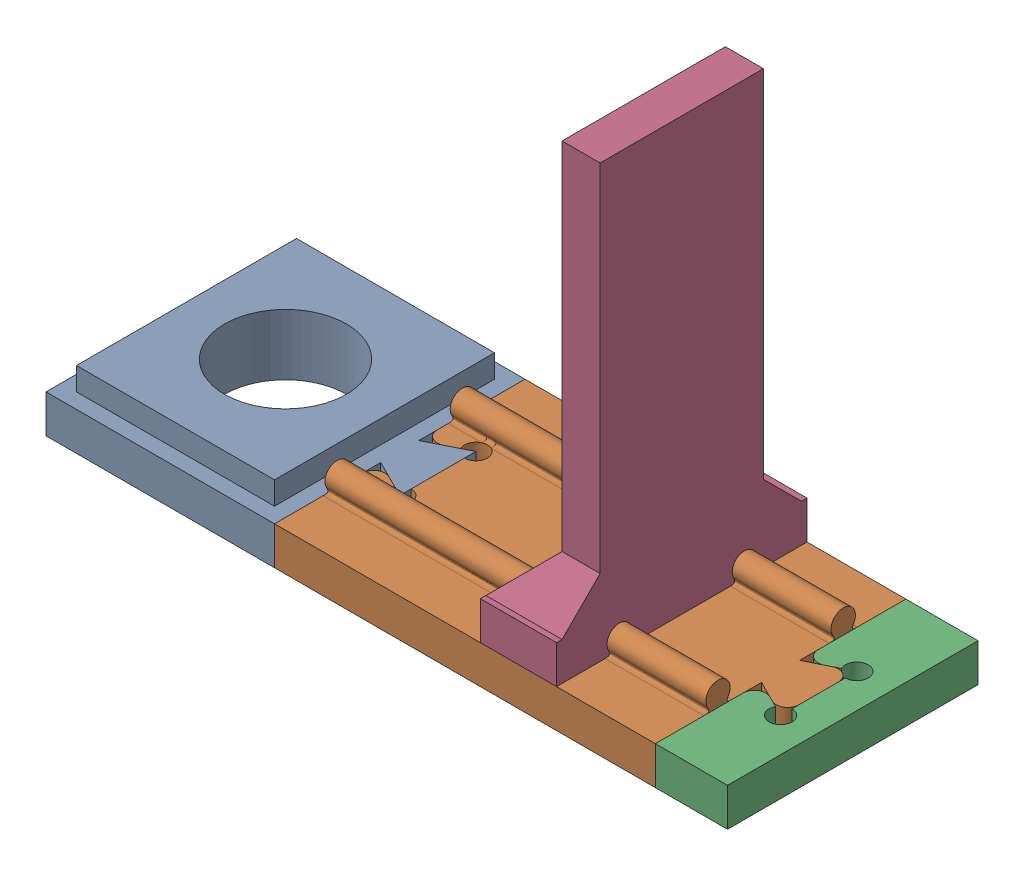
SolidWorks assembly 2.2.2.1_Mono_Guia_Lineal, configuration Predeterminado. Lengths in mm.
Overall size (89.47 61.68 32.88).
4 component instances, 4 part files, 10 mates.
Components (placement in the parent):
- 2.1.2.2.6_Base_Sujetador-1: 2.1.2.2.6_Base_Sujetador [Predeterminado] at (-44.4459 -5.7383 3.6115) x (-1 0 0) z (0 -1 0) size (35 32.88 8)
- 2.1.2.2.7_Segmento_Riel-1: 2.1.2.2.7_Segmento_Riel [Predeterminado] at (-54.4459 -13.7383 3.6115) x (-1 0 0) z (0 -1 0) size (55.01 32.88 8.1)
- 2.1.2.2.8_Segmento_Final_De_Riel-1: 2.1.2.2.8_Segmento_Final_De_Riel [Predeterminado] at (-54.4459 -13.7383 3.6115) x (-1 0 0) z (0 -1 0) size (9.47 32.88 5)
- 2.1.2.2.9_Pared_De_Rebote-1: 2.1.2.2.9_Pared_De_Rebote [Predeterminado] at (-3.4196 -13.7383 3.6115) x (0 -1 0) z (1 0 0) size (56.68 32.88 10.01)
Mates (geometry in assembly coordinates):
- Paralelo1: parallel anti-aligned: plane of 2.1.2.2.6_Base_Sujetador-1 through (-44.4459 -13.7383 3.6115) normal (0 -1 0)
- Paralelo2: parallel aligned: plane of 2.1.2.2.6_Base_Sujetador-1 through (-40.4459 -13.7383 10.8963) normal (0 0 1)
- Coincidente3: coincident anti-aligned: plane of 2.1.2.2.6_Base_Sujetador-1 through (-35.4459 -8.7383 -10.5461) normal (-0.447214 0 -0.894427); plane of 2.1.2.2.7_Segmento_Riel-1 through (-56.309 55.3429 -0.1146) normal (0.447214 0 0.894427)
- Coincidente4: coincident anti-aligned: plane of 2.1.2.2.6_Base_Sujetador-1 through (-35.4459 -8.7383 -0.5461) normal (-0.447214 0 0.894427); plane of 2.1.2.2.7_Segmento_Riel-1 through (-48.9829 55.3429 -7.3146) normal (0.447214 0 -0.894427)
- Coincidente5: coincident aligned: plane of 2.1.2.2.6_Base_Sujetador-1 through (-44.4459 -8.7383 3.6115) normal (0 1 0); plane of 2.1.2.2.7_Segmento_Riel-1 through (-54.4459 -8.7383 3.6115) normal (0 1 0)
- Coincidente6: coincident anti-aligned: plane of 2.1.2.2.7_Segmento_Riel-1 through (-38.9829 55.3429 -27.3146) normal (-0.447214 0 0.894427); plane of 2.1.2.2.8_Segmento_Final_De_Riel-1 through (14.5541 25.4832 -0.5461) normal (0.447214 0 -0.894427)
- Coincidente7: coincident anti-aligned: plane of 2.1.2.2.7_Segmento_Riel-1 through (-46.309 55.3429 19.8854) normal (-0.447214 0 -0.894427); plane of 2.1.2.2.8_Segmento_Final_De_Riel-1 through (9.5541 25.4832 -8.0461) normal (0.447214 0 0.894427)
- Coincidente8: coincident aligned: plane of 2.1.2.2.7_Segmento_Riel-1 through (-54.4459 -8.7383 3.6115) normal (0 1 0); plane of 2.1.2.2.8_Segmento_Final_De_Riel-1 through (-54.4459 -8.7383 3.6115) normal (0 1 0)
- Concéntrica1: concentric aligned: cylinder of 2.1.2.2.7_Segmento_Riel-1 through (-44.9714 -7.2383 2.6751) axis (1 0 0) radius 1.6; cylinder of 2.1.2.2.9_Pared_De_Rebote-1 through (-13.4196 -7.2383 2.6751) axis (1 0 0) radius 1.6
- Concéntrica2: concentric aligned: cylinder of 2.1.2.2.7_Segmento_Riel-1 through (-44.9714 -7.2383 -13.7673) axis (1 0 0) radius 1.6; cylinder of 2.1.2.2.9_Pared_De_Rebote-1 through (-13.4196 -7.2383 -13.7673) axis (1 0 0) radius 1.6
